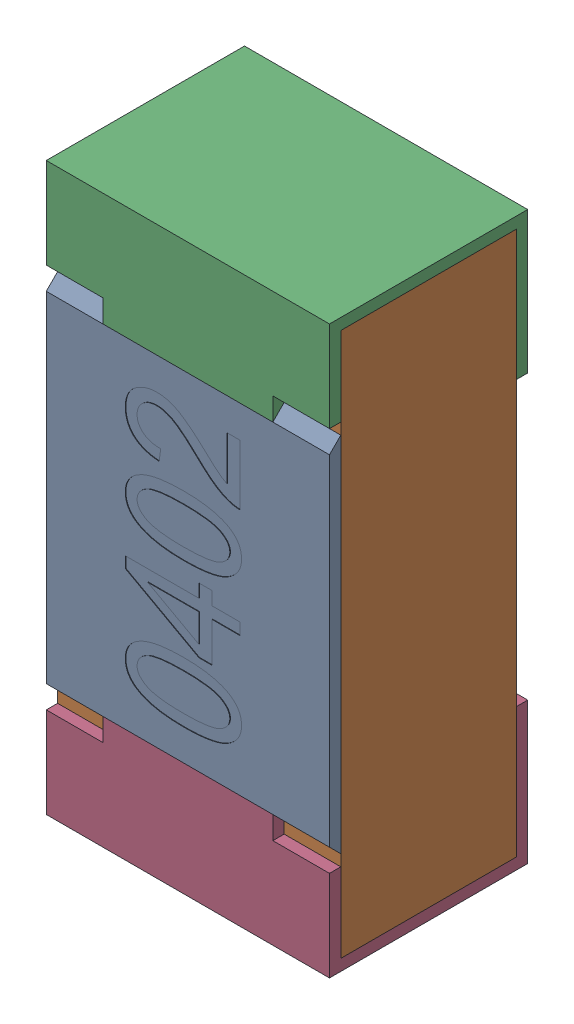
SolidWorks assembly R28, configuration Standard. Lengths in mm.
Overall size (0.5 1 0.35).
5 component instances, 4 part files, 0 mates.
Components (placement in the parent):
- R28-subassembly-1-1: R28-subassembly-1 [Standard] at (-15.5 3.9001 0) x (0 1 0) z (0 0 1) size (1 0.5 0.35)
  - User Library-R_0402-1: User Library-R_0402 [Standard] at origin size (0.64 0.5 0.02)
  - User Library-R_0402-1-1: User Library-R_0402-1 [Standard] at origin size (0.96 0.5 0.31)
  - User Library-R_0402-2-1: User Library-R_0402-2 [Standard] at origin size (0.25 0.5 0.35)
  - User Library-R_0402-3-1: User Library-R_0402-3 [Standard] at origin size (0.25 0.5 0.35)
